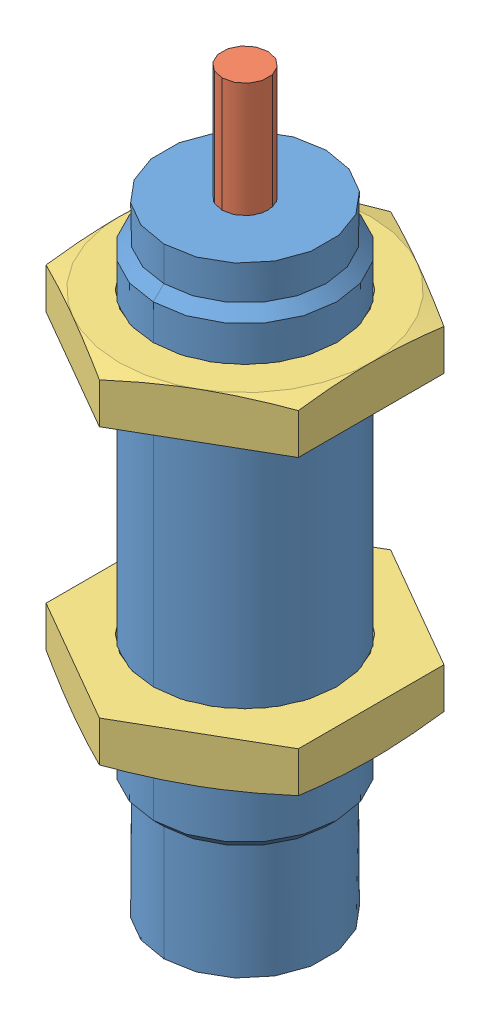
SolidWorks assembly MAKS0805A, configuration Default. Lengths in mm.
Overall size (12.6 32 12.71).
4 component instances, 3 part files, 0 mates.
Components (placement in the parent):
- _MAKS0805Ab_2-1: _MAKS0805Ab_2 [Default] at origin size (8 27 8)
- _MAKS0805Ar_4-1: _MAKS0805Ar_4 [Default] at (0 22 0) size (2 16 2)
- _M8x0_75211N2_6-1: _M8x0_75211N2_6 [Default] at (0 4.5 0) x (0 -1 0) z (-1 0 0) size (2.01 12.71 12.6)
- _M8x0_75211N2_6-2: _M8x0_75211N2_6 [Default] at (0 17.5 0) x (0 1 0) z (-1 0 0) size (2.01 12.71 12.6)
